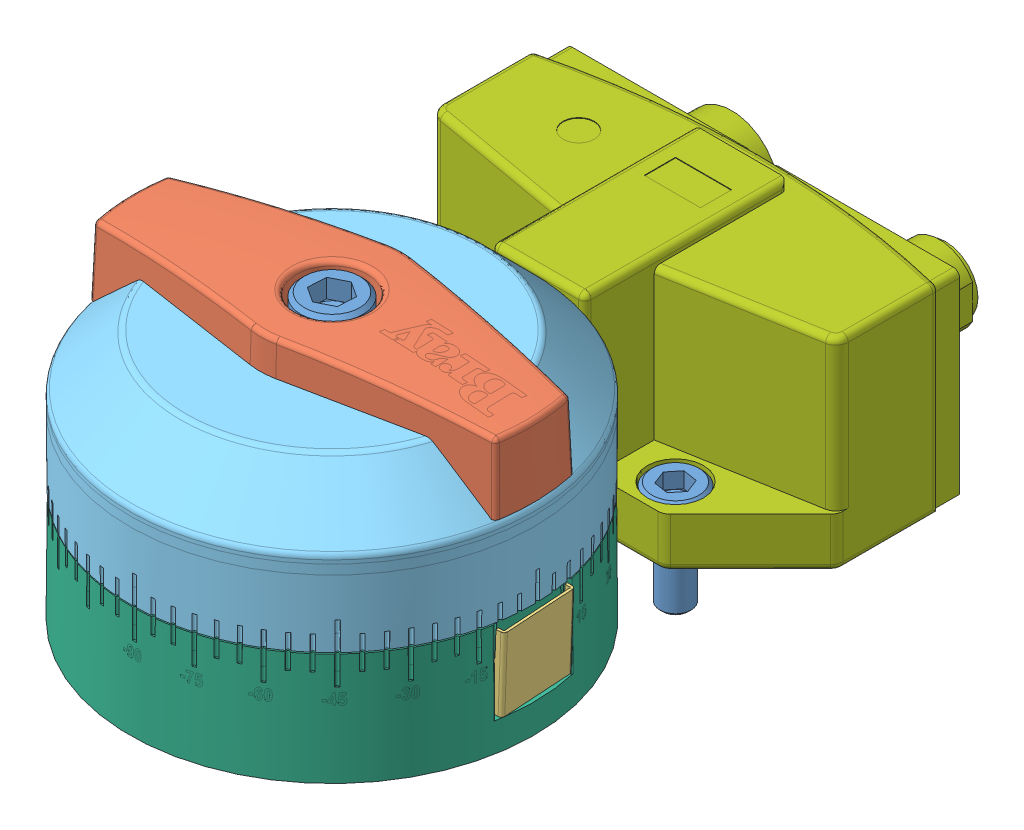
SolidWorks assembly SIZE 063-093, configuration Default. Lengths in mm.
Overall size (66.08 56.14 114.78).
10 component instances, 7 part files, 10 mates.
Components (placement in the parent):
- socket head cap screw_am-1: socket head cap screw_am [B18.3.1M - 6 x 1.0 x 30 Hex SHCS -- 30NHX] at (2.0563 173.3329 -7.3131) x (0 -1 0) z (-0.546944 0 0.837169) size (36 10 10)
- socket head cap screw_am-2: socket head cap screw_am [B18.3.1M - 5 x 0.8 x 12 Hex SHCS -- 12NHX] at (-12.9551 134.5151 -47.3181) x (0 -1 0) z (-0.778168 0 0.628056) size (17 8.5 8.5)
- socket head cap screw_am-3: socket head cap screw_am [B18.3.1M - 5 x 0.8 x 12 Hex SHCS -- 12NHX] at (17.0677 134.5151 -47.3181) x (0 -1 0) z (-0.778168 0 -0.628056) size (17 8.5 8.5)
- 54-000A-92512-1: 54-000A-92512 [Default] at (2.0563 161.9989 -7.3131) x (-0.999645 0 0.026634) z (-0.026634 0 -0.999645) size (64.52 13.44 23.07)
- 54-000A-73500-1: 54-000A-73500 [Default] at (34.5056 139.1679 -7.97) x (-0.060648 0.001457 -0.998158) z (0.997549 -0.034869 -0.060662) size (12.19 11.94 6.35)
- 54-000A-73500-2: 54-000A-73500 [Default] at (1.5249 152.0929 -39.9699) x (-0.999979 0 0.00653) z (-0.00653 0 -0.999979) size (12.19 11.94 6.35)
- 54-048A-705P0-1: 54-048A-705P0 [Default] at (2.0563 155.4711 -7.3131) size (44.92 12.57 44.92)
- 54-000A-92511-1: 54-000A-92511 [Default] at (2.0563 146.1239 -7.3131) x (-0.999796 0 0.020182) z (-0.020182 0 -0.999796) size (64.76 21.97 66.01)
- 54-000A-92510-1: 54-000A-92510 [Default] at (2.0563 128.0391 -7.3131) x (-0.018943 0 -0.999821) z (0.999821 0 -0.018943) size (64.81 35.64 64.77)
- 54-0005-71104-1: 54-0005-71104 [Default] at (2.0677 126.5151 -75.8181) size (65 33.5 48.75)
Mates (geometry in assembly coordinates):
- Coincident1: coincident: plane of socket head cap screw_am-1 through (6.2421 167.3329 -4.5784) normal (0 -1 0); circle of 54-000A-92512-1
- Tangent1: tangent: line of 54-000A-73500-2 through (7.6242 146.1239 -39.4763) axis (0 1 0); face of 54-000A-92511-1
- Coincident2: coincident: plane of 54-000A-92511-1 through (2.3103 158.6461 5.27) normal (0 -1 0); plane of 54-000A-92510-1 through (1.8133 158.6461 -20.1378) normal (0 1 0)
- Parallel1: parallel: plane of 54-000A-73500-1 through (34.6671 133.1937 -1.8813) normal (-0.034893 -0.999391 0.000661); plane of 54-000A-92510-1 through (32.48 132.6873 -7.8895) normal (0.034893 0.999391 -0.000661)
- Coincident3: coincident: plane of 54-048A-705P0-1 through (2.0563 155.4711 -7.3131) normal (0 1 0); plane of 54-000A-92510-1 through (1.6497 155.4711 -28.7722) normal (0 -1 0)
- Coincident4: coincident: plane of 54-000A-73500-2 through (7.6207 146.1239 -40.0097) normal (0 -1 0); plane of 54-000A-92511-1 through (2.6563 146.1239 22.4083) normal (0 -1 0)
- Distance1: distance = 0.1778 mm: plane of 54-000A-92511-1 through (2.2588 161.8211 2.7179) normal (0 1 0); plane of 54-000A-92512-1 through (2.2535 161.9989 0.0884) normal (0 -1 0)
- Concentric1: concentric: cylinder of 54-000A-92512-1 through (2.0563 161.9989 -7.3131) axis (0 -1 0) radius 3.3; cylinder of 54-000A-92510-1 through (2.0563 118.7053 -7.3131) axis (0 1 0) radius 3.3
- Concentric2: concentric: cylinder of 54-000A-92512-1 through (2.0563 161.9989 -7.3131) axis (0 -1 0) radius 3.3; cylinder of 54-000A-92511-1 through (2.0563 149.3123 -7.3131) axis (0 1 0) radius 3.3
- Concentric3: concentric: cylinder of socket head cap screw_am-1 through (2.0563 205.0829 -7.3131) axis (0 1 0) radius 3; cylinder of 54-000A-92512-1 through (2.0563 161.9989 -7.3131) axis (0 -1 0) radius 3.3
